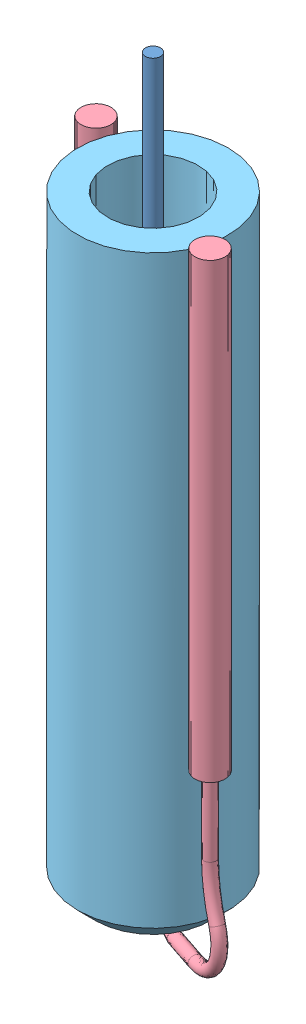
SolidWorks assembly Nozzle, configuration Default. Lengths in mm.
Overall size (14.64 50.5 10.57).
7 component instances, 6 part files, 13 mates.
Components (placement in the parent):
- AluminumWire-1: AluminumWire [Default] at origin size (1 50.5 1)
- GlassTube_1-1: GlassTube_1 [Default] at (0 1 0) size (3 30 3)
- Nichrome_Coil-1: Nichrome_Coil [Default] at (0 1.9147 0) x (0.999996 0 0.002658) z (-0.002658 0 0.999996) size (3.57 26.5 7)
- Electrode-1: Electrode [Default] at (0 0.6 0) x (-0.948172 0 -0.317757) z (0.317757 0 -0.948172) size (6.9 42.34 2)
- Electrode-2: Electrode [Default] at (0 0.6 0) x (0.948172 0 0.317757) z (-0.317757 0 0.948172) size (6.9 42.34 2)
- GlassTube_2-1: GlassTube_2 [Default] at (0 2 0) x (-0.058842 0 -0.998267) z (0.998267 0 -0.058842) size (10 40 10)
- SteelPutty-1: SteelPutty [Default] at (0 19.4588 0) x (0.96725 0 0.253826) z (-0.253826 0 0.96725) size (6 2 6)
Mates (geometry in assembly coordinates):
- Coincident1: coincident aligned: plane of AluminumWire-1 through (0 0 0) normal (0 0 1); plane of assembly through (0 0 0) normal (0 0 1)
- Coincident2: coincident aligned: plane of AluminumWire-1 through (0 0 0) normal (1 0 0); plane of assembly through (0 0 0) normal (1 0 0)
- Coincident3: coincident aligned: plane of AluminumWire-1 through (0 0 0) normal (0 1 0); plane of assembly through (0 0 0) normal (0 1 0)
- Concentric1: concentric anti-aligned: cylinder of AluminumWire-1 through (0 0 0) axis (0 1 0) radius 0.5; cylinder of GlassTube_1-1 through (0 1 0) axis (0 -1 0) radius 1.5
- Distance1: distance = 1 mm aligned: plane of GlassTube_1-1 through (0.6 1 0) normal (0 -1 0); moEndPointRef_w of AluminumWire-1
- Concentric2: concentric aligned: cylinder of GlassTube_1-1 through (0 1 0) axis (0 -1 0) radius 1.5; line of Nichrome_Coil-1 through (0 12.4397 0) axis (0 -1 0)
- Concentric3: concentric aligned: cylinder of AluminumWire-1 through (0 0 0) axis (0 1 0) radius 0.5; cylinder of Electrode-2 through (0 0.2 0) axis (0 1 0) radius 0.5
- Concentric4: concentric aligned: cylinder of AluminumWire-1 through (0 0 0) axis (0 1 0) radius 0.5; cylinder of Electrode-1 through (0 0.2 0) axis (0 1 0) radius 0.5
- Concentric5: concentric anti-aligned: cylinder of Electrode-1 through (0 0.6 0) axis (-0.948172 0 -0.317757) radius 0.4; cylinder of Electrode-2 through (0 0.6 0) axis (0.948172 0 0.317757) radius 0.4
- Tangent2: tangent anti-aligned: plane of GlassTube_1-1 through (0.6 1 0) normal (0 -1 0); cylinder of Electrode-1 through (0 0.6 0) axis (-0.948172 0 -0.317757) radius 0.4
- Concentric6: concentric aligned: cylinder of GlassTube_1-1 through (0 1 0) axis (0 -1 0) radius 1.5; cylinder of GlassTube_2-1 through (0 2 0) axis (0 -1 0) radius 5
- Distance2: distance = 1 mm aligned: plane of GlassTube_1-1 through (0.6 1 0) normal (0 -1 0); plane of GlassTube_2-1 through (-0.1765 2 -2.9948) normal (0 -1 0)
- Concentric7: concentric aligned: cylinder of GlassTube_2-1 through (0 2 0) axis (0 -1 0) radius 5; cylinder of SteelPutty-1 through (0 19.4588 0) axis (0 -1 0) radius 3
